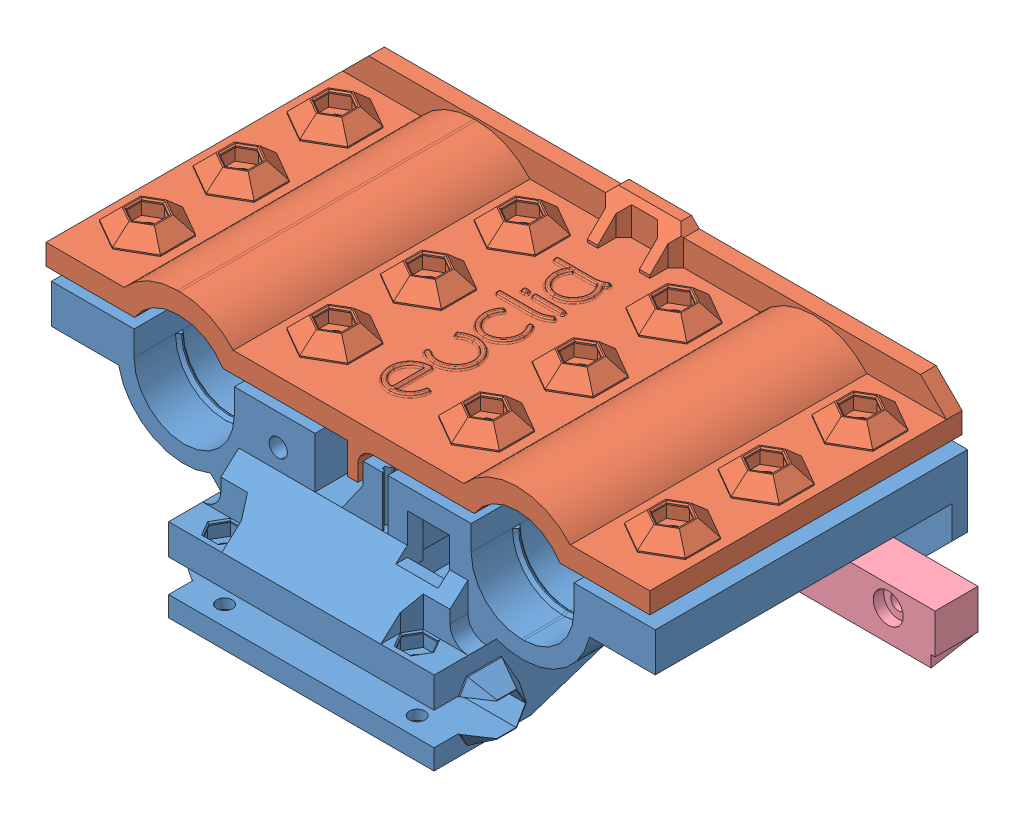
SolidWorks assembly carriage-plate-3x, configuration Default. Lengths in mm.
Overall size (120 50.21 70).
4 component instances, 4 part files, 10 mates.
Components (placement in the parent):
- carriage-front-lm10luu-1: carriage-front-lm10luu [Default] at (188.5248 -6.5699 60) x (-1 0 0) z (0 -1 0) size (116 70 34.75)
- carriage-back-lm10luu-1: carriage-back-lm10luu [Default] at (187.4748 -4.8573 0) x (1 0 0) z (0 -1 0) size (116 60 16.5)
- standoff-cover-lm10luu-1: standoff-cover-lm10luu [Default] at (158.5248 -9.5699 12) x (1 0 0) z (0 -1 0) size (60 9.59 16)
- belt-wedge-lm10luu-1: belt-wedge-lm10luu [Default] at (191.5248 -42.0699 -0.75) x (0 -1 0) z (0 0 1) size (9.85 57 8.25)
Mates (geometry in assembly coordinates):
- Coincident1: coincident anti-aligned: plane of carriage-front-lm10luu-1 through (192.8748 -15.4606 0) normal (0 0 -1); plane of assembly through (0 0 0) normal (0 0 1)
- Distance1: distance = 1 mm anti-aligned: plane of carriage-back-lm10luu-1 through (189.3748 -5.8573 0) normal (1 0 0); plane of carriage-front-lm10luu-1 through (190.3748 -15.4606 32) normal (-1 0 0)
- Coincident7: coincident aligned: plane of carriage-front-lm10luu-1 through (192.8748 -15.4606 0) normal (0 0 -1); plane of standoff-cover-lm10luu-1 through (202.6775 -39.5699 0) normal (0 0 -1)
- Coincident9: coincident aligned: plane of carriage-front-lm10luu-1 through (192.8748 -15.4606 0) normal (0 0 -1); plane of belt-wedge-lm10luu-1 through (294.0248 15.9301 0) normal (0 0 -1)
- Distance3: distance = 3 mm anti-aligned: plane of carriage-front-lm10luu-1 through (246.5248 -20.5699 0) normal (0 -1 0); plane of belt-wedge-lm10luu-1 through (248.5248 -23.5699 -59.0084) normal (0 1 0)
- Coincident10: coincident anti-aligned: plane of carriage-back-lm10luu-1 through (189.9748 -4.8573 0) normal (0 0 -1); plane of assembly through (0 0 0) normal (0 0 1)
- Coincident11: coincident: line of carriage-front-lm10luu-1 through (192.8748 -5.8573 22) axis (0 0 1); plane of carriage-back-lm10luu-1 through (189.9748 -5.8573 0) normal (0 -1 0)
- Coincident12: coincident aligned: plane of standoff-cover-lm10luu-1 through (202.6775 -23.5699 2) normal (0 1 0); plane of belt-wedge-lm10luu-1 through (251.0248 -23.5699 -59.0084) normal (0 1 0)
- Distance4: distance = 2 mm aligned: plane of carriage-front-lm10luu-1 through (246.5248 7.4301 0) normal (1 0 0); plane of belt-wedge-lm10luu-1 through (248.5248 -31.1999 -59.0084) normal (1 0 0)
- Distance5: distance = 2 mm aligned: plane of carriage-front-lm10luu-1 through (130.5248 7.4301 0) normal (-1 0 0); plane of standoff-cover-lm10luu-1 through (128.5248 -9.5699 12) normal (-1 0 0)
